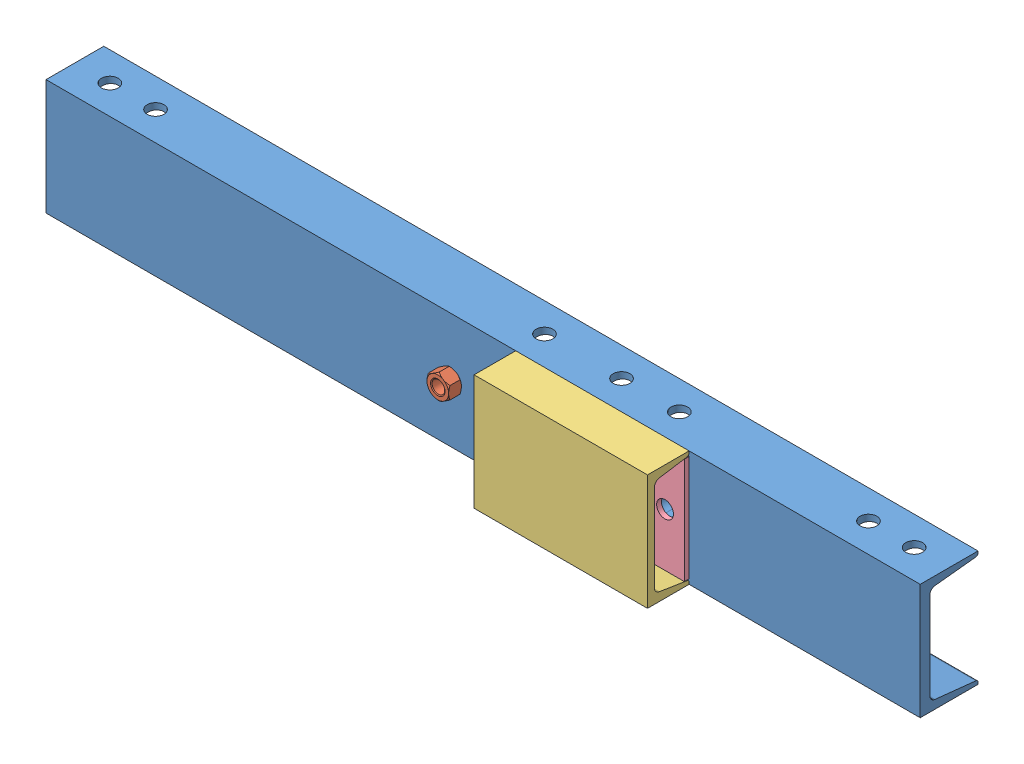
SolidWorks assembly 01-114-00-0, configuration Default. Lengths in mm.
Overall size (1152.53 152.4 131.06).
5 component instances, 4 part files, 11 mates.
Components (placement in the parent):
- 01-015-00-0-2: 01-015-00-0 [Default] at origin size (1152.53 152.4 76.2)
- hex nut_ai-1: hex nut_ai [HNUT 0.7500-10-D-C] at (-42.8625 0 65.6971) size (28.57 33 16.89)
- 01-034-00-0-1: 01-034-00-0 [Default] at (157.2895 0 78.3336) size (228.6 152.4 54.86)
- Compression Spacer backing plate-1: Compression Spacer backing plate [Default] at (42.9895 -69.85 48.8061) x (0 1 0) z (1 0 0) size (139.7 6.35 50.8)
- Compression Spacer backing plate-2: Compression Spacer backing plate [Default] at (220.7895 -69.85 48.8061) x (0 1 0) z (1 0 0) size (139.7 6.35 50.8)
Mates (geometry in assembly coordinates):
- Coincident1: coincident anti-aligned: plane of 01-015-00-0-2 through (576.2625 -76.2 48.8061) normal (0 0 1); plane of hex nut_ai-1 through (-42.8625 16.4978 48.8061) normal (0 0 -1)
- Coincident1122: coincident anti-aligned: plane of 01-015-00-0-2 through (576.2625 -76.2 48.8061) normal (0 0 1); plane of 01-034-00-0-1 through (271.5895 -76.2 48.8061) normal (0 0 -1)
- Coincident1124: coincident aligned: plane of 01-015-00-0-2 through (576.2625 -76.2 48.8061) normal (0 -1 0); plane of 01-034-00-0-1 through (271.5895 -76.2 103.6701) normal (0 -1 0)
- Distance1: distance = 847.852 mm anti-aligned: plane of 01-034-00-0-1 through (271.5895 -73.7107 51.8541) normal (1 0 0); plane of 01-015-00-0-2 through (-576.2625 -73.7107 -24.3459) normal (-1 0 0)
- Concentric1: concentric anti-aligned: cylinder of 01-015-00-0-2 through (-42.8625 0 48.8061) axis (0 0 -1) radius 11.1125; cylinder of hex nut_ai-1 through (-42.8625 0 48.8061) axis (0 0 1) radius 8.3337
- Coincident1125: coincident anti-aligned: plane of 01-015-00-0-2 through (576.2625 -76.2 48.8061) normal (0 0 1); plane of Compression Spacer backing plate-1 through (42.9895 -69.85 48.8061) normal (0 0 -1)
- Distance2: distance = 6.35 mm aligned: plane of Compression Spacer backing plate-1 through (42.9895 -69.85 55.1561) normal (0 -1 0); plane of 01-015-00-0-2 through (576.2625 -76.2 48.8061) normal (0 -1 0)
- Coincident1127: coincident aligned: plane of 01-034-00-0-1 through (42.9895 -73.7107 51.8541) normal (-1 0 0); plane of Compression Spacer backing plate-1 through (42.9895 -69.85 55.1561) normal (-1 0 0)
- Coincident1128: coincident anti-aligned: plane of 01-015-00-0-2 through (576.2625 -76.2 48.8061) normal (0 0 1); plane of Compression Spacer backing plate-2 through (220.7895 -69.85 48.8061) normal (0 0 -1)
- Coincident1129: coincident aligned: plane of 01-034-00-0-1 through (271.5895 -73.7107 51.8541) normal (1 0 0); plane of Compression Spacer backing plate-2 through (271.5895 -69.85 55.1561) normal (1 0 0)
- Distance3: distance = 6.35 mm aligned: plane of Compression Spacer backing plate-2 through (220.7895 -69.85 55.1561) normal (0 -1 0); plane of 01-015-00-0-2 through (576.2625 -76.2 48.8061) normal (0 -1 0)
